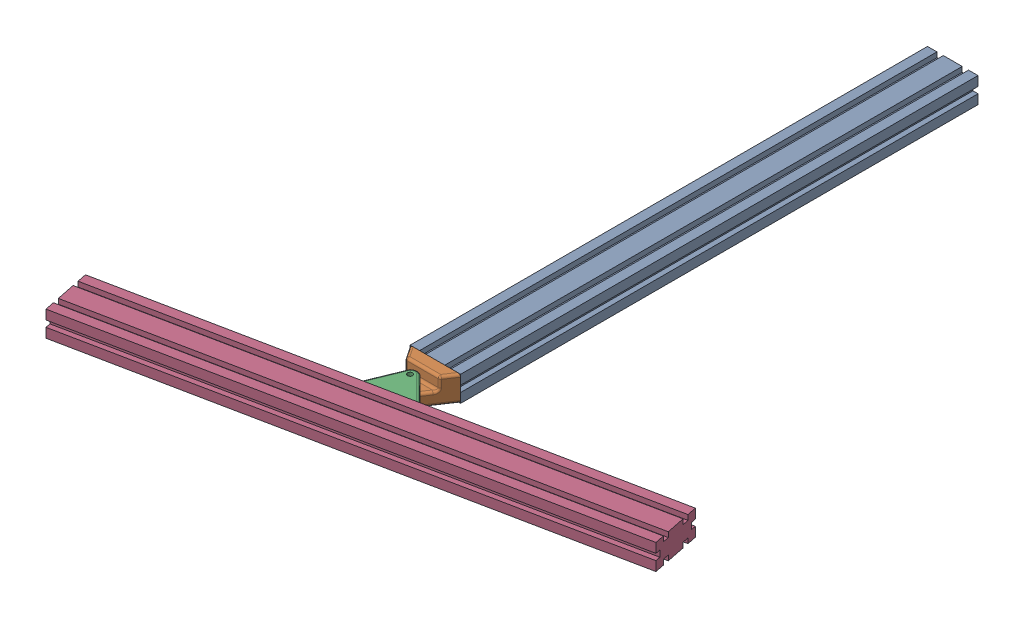
SolidWorks assembly Pivot, configuration Défaut. Lengths in mm.
Overall size (409.77 20.22 529.57).
4 component instances, 2 part files, 11 mates.
Components (placement in the parent):
- profilé 410 20 40 - Copie-1: profilé 410 20 40 - Copie [Défaut] at (-40 -20 -410) size (40 20 410)
- pivot2024-1: pivot2024 [Défaut] at (-40 -20 0) x (0 0 1) z (-1 0 0) size (25.75 20.11 40)
- pivot2024-2: pivot2024 [Défaut] at (-35.6235 0 43.5777) x (-0.198856 0 -0.980029) z (-0.980029 0 0.198856) size (25.75 20.11 40)
- profilé 410 20 40 - Copie-2: profilé 410 20 40 - Copie [Défaut] at (-208.9746 -20 119.5672) x (-0.198856 0 -0.980029) z (0.980029 0 -0.198856) size (40 20 410)
Mates (geometry in assembly coordinates):
- Coïncidente2: coincident aligned: plane of profilé 410 20 40 - Copie-1 through (-40 -20 0) normal (0 0 1)
- Coïncidente3: coincident aligned: plane of profilé 410 20 40 - Copie-1 through (0 -20 0) normal (1 0 0)
- Coïncidente4: coincident aligned: plane of profilé 410 20 40 - Copie-1 through (-40 0 0) normal (0 1 0)
- Coïncidente5: coincident anti-aligned: line of profilé 410 20 40 - Copie-1 through (-27.5 0 0) axis (1 0 0); line of pivot2024-1 through (-2.4037 0 0) axis (-1 0 0)
- Coïncidente6: coincident anti-aligned: line of profilé 410 20 40 - Copie-1 through (-40 -7.5 0) axis (0 1 0); line of pivot2024-1 through (-40 -2 0) axis (0 -1 0)
- Coaxiale1: concentric anti-aligned: cylinder of pivot2024-1 through (-20 -10 20) axis (0 -1 0) radius 2; cylinder of pivot2024-2 through (-20 -10 20) axis (0 1 0) radius 2
- Coïncidente7: coincident anti-aligned: plane of pivot2024-1 through (-40 -10 0) normal (0 1 0); plane of pivot2024-2 through (-35.6235 -10 43.5777) normal (0 -1 0)
- AngleLimite1: limit planar angle = 0.20019 rad anti-aligned: plane of pivot2024-2 through (-35.6235 -10 43.5777) normal (0.198856 0 0.980029); plane of pivot2024-1 through (-40 -10 0) normal (0 0 -1)
- Coïncidente9: coincident anti-aligned: plane of pivot2024-2 through (-35.6235 -10 43.5777) normal (0.198856 0 0.980029); plane of profilé 410 20 40 - Copie-2 through (184.883 -20 -1.1648) normal (-0.198856 0 -0.980029)
- Coïncidente10: coincident: point of pivot2024-2; unknown of profilé 410 20 40 - Copie-2
- Parallèle1: parallel aligned: line of pivot2024-2 through (3.5777 -18 35.6235) axis (0 1 0); line of profilé 410 20 40 - Copie-2 through (184.883 -7.5 -1.1648) axis (0 1 0)
